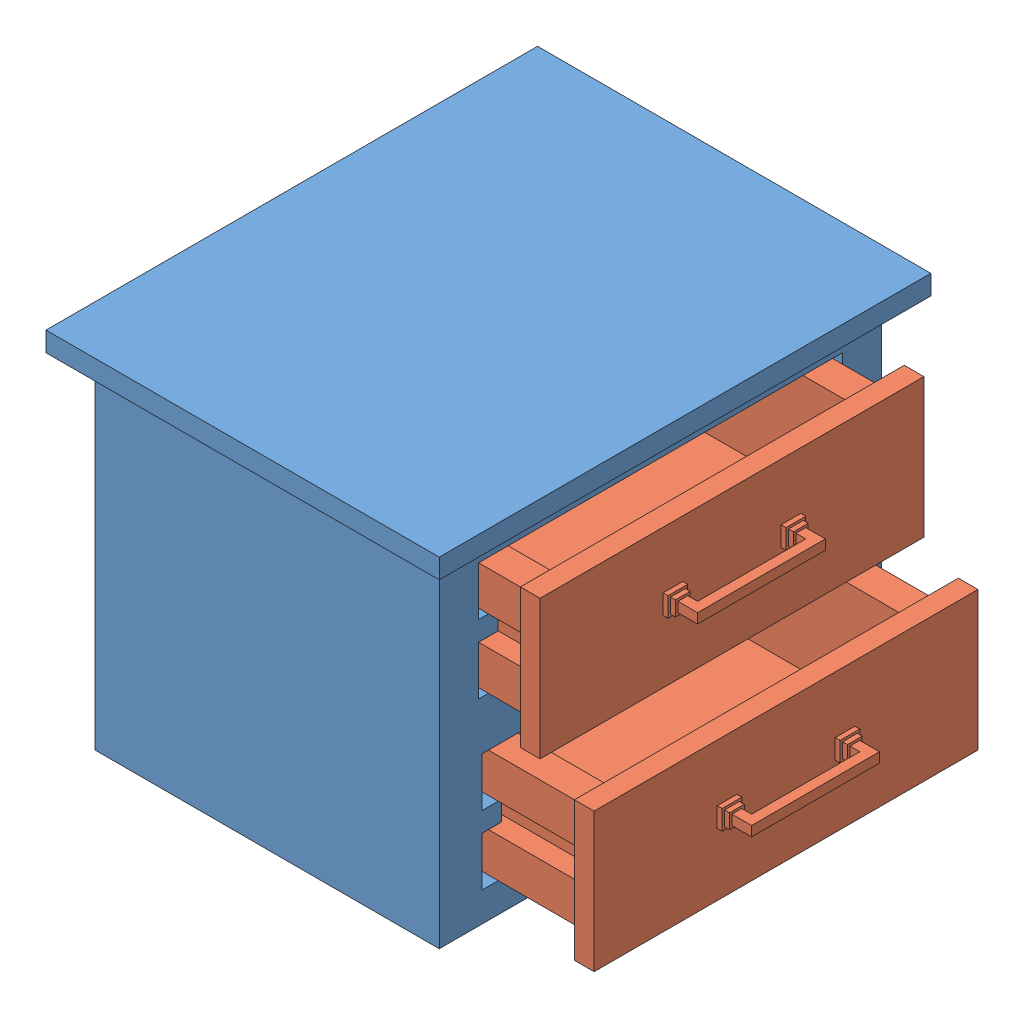
SolidWorks assembly Cupboard, configuration Default. Lengths in mm.
Overall size (525 370 500).
3 component instances, 2 part files, 6 mates.
Components (placement in the parent):
- C-Part 01-1: C-Part 01 [Default] at (-31.0601 438.2103 503.9112) size (400 370 500)
- C-Part 02-1: C-Part 02 [Default] at (193.9399 324.9725 501.1653) x (0 0 -1) z (1 0 0) size (390.49 141.48 370)
- C-Part 02-2: C-Part 02 [Default] at (243.9399 159.9725 496.1653) x (0 0 -1) z (1 0 0) size (390.49 141.48 370)
Mates (geometry in assembly coordinates):
- Distance2: distance = 2.5 mm: plane of Commode-1 through (-176.0601 388.2103 318.9112) normal (0 0 1); plane of Cupboard-1 through (-126.0601 380.7103 321.4112) normal (0 0 -1)
- Distance1: distance = 2.5 mm: plane of Commode-1 through (-176.0601 268.2103 688.9112) normal (0 1 0); plane of Cupboard-1 through (-126.0601 270.7103 681.4112) normal (0 -1 0)
- Distance3: distance = 50 mm anti-aligned: plane of Cupboard-1 through (193.9399 324.9725 501.1653) normal (-1 0 0); plane of Commode-1 through (143.9399 68.2103 728.9112) normal (1 0 0)
- Distance4: distance = 2.5 mm: plane of Cupboard-2 through (-76.0601 215.7103 316.4112) normal (0 0 -1); plane of Commode-1 through (-176.0601 218.2103 318.9112) normal (0 0 1)
- Distance5: distance = 2.5 mm: plane of Commode-1 through (-176.0601 218.2103 685.3901) normal (0 -1 0); plane of Cupboard-2 through (-76.0601 215.7103 676.4112) normal (0 1 0)
- Distance6: distance = 100 mm anti-aligned: plane of Commode-1 through (143.9399 68.2103 728.9112) normal (1 0 0); plane of Cupboard-2 through (243.9399 159.9725 496.1653) normal (-1 0 0)
